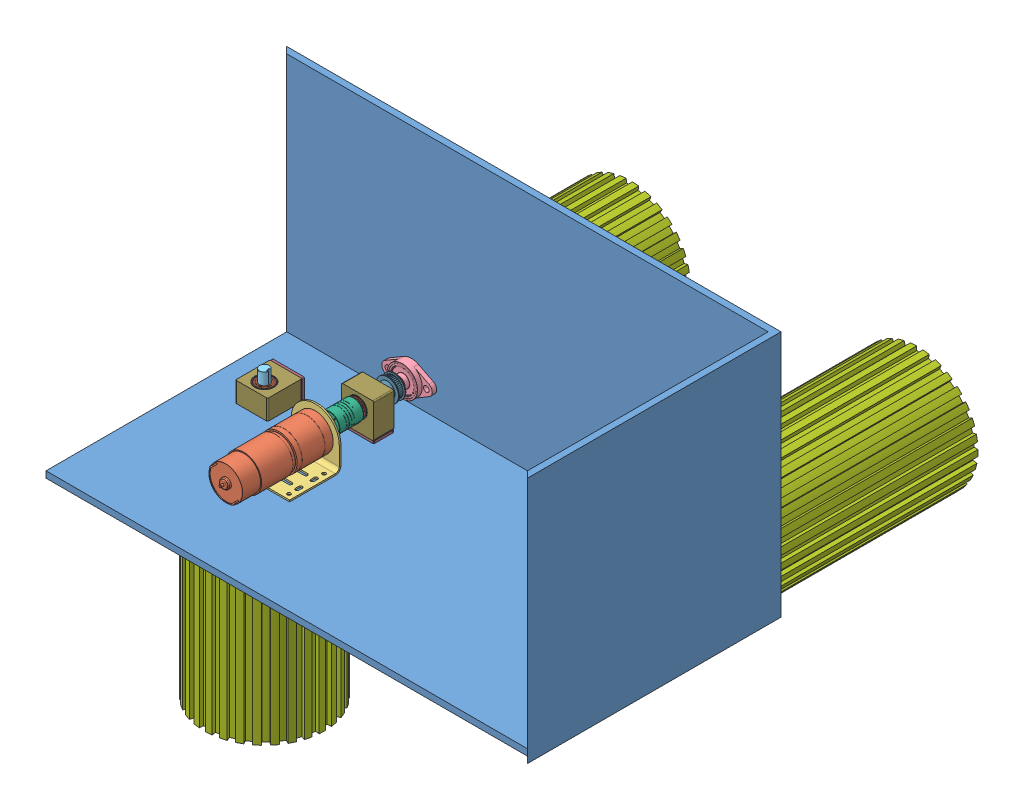
SolidWorks assembly moter in box assemly2, configuration Default. Lengths in mm.
Overall size (629.9 614.4 580.4).
108 component instances, 14 part files, 29 mates.
Components (placement in the parent):
- box-1: box [Default] at (214.7869 209.4239 556.9442) size (616 308 316)
- Motor DC PG45-1: Motor DC PG45 [Default] at (70.1664 247.4239 638.3442) x (0.707107 0.707107 0) z (-0.707107 0.707107 0) size (45 146.01 45)
- Mounting Bracket Motor DC PG45 Orange-1: Mounting Bracket Motor DC PG45 Orange [Default] at (91.7552 243.9192 526.8442) x (-1 0 0) z (0 0 -1) size (60 60 63.93)
- KFL001 block flange ball bearing 12 diameter shaft-1: KFL001 block flange ball bearing 12 diameter shaft [Default] at (70.1664 247.4239 406.9442) x (-0.034258 0.999413 0) z (0.999413 0.034258 0) size (38 16 63)
- wheel shaft-1: wheel shaft [Default] at (70.1664 247.4239 234.5442) x (0.995554 -0.094191 0) z (-0.094191 -0.995554 0) size (12 354 12)
- Shaft_Coupler_6.35x12mm-1: Shaft_Coupler_6.35x12mm [По умолчанию] at (70.1664 247.4239 508.9442) x (0.647293 0.762241 0) z (-0.762241 0.647293 0) size (25.41 30 25.41)
- wheel rubber-1: wheel rubber [Default] at (70.1664 247.4239 134.5442) x (-0.995554 0.094191 0) z (0.094191 0.995554 0) size (149.8 250 150)
- wheel rim-1: wheel rim [Default] at (70.1664 247.4239 134.5442) x (-0.995554 0.094191 0) z (0.094191 0.995554 0) size (130 250 130)
- Bearing House v1.step-1: Bearing House v1.step [Default] at (70.1664 227.9239 462.9398) x (-1 0 0) z (0 1 0) size (40 25 45.94)
  - SKF_61901-2Z.step-1: SKF_61901-2Z.step [Default] at (0 -8 19.5) x (0 -1 0) z (0 0 1) size (6 24 24)
    - SKF_61901-2Z_ball1.step-1: SKF_61901-2Z_ball1.step [Default] at (6 16.2812 -5.2901) x (-1 0 0) z (0 0 1) size (3.18 3.17 3.17)
    - SKF_61901-2Z_ball1.step-2: SKF_61901-2Z_ball1.step [Default] at (6 11.7812 -8.5595) x (-1 0 0) z (0 0 1) size (3.18 3.17 3.17)
    - SKF_61901-2Z_ball1.step-3: SKF_61901-2Z_ball1.step [Default] at (6 6.2188 -8.5595) x (-1 0 0) z (0 0 1) size (3.18 3.17 3.17)
    - SKF_61901-2Z_ball1.step-4: SKF_61901-2Z_ball1.step [Default] at (6 1.7188 -5.2901) x (-1 0 0) z (0 0 1) size (3.18 3.17 3.17)
    - SKF_61901-2Z_ball1.step-5: SKF_61901-2Z_ball1.step [Default] at (6 0 0) x (-1 0 0) z (0 0 1) size (3.18 3.17 3.17)
    - SKF_61901-2Z_ball1.step-6: SKF_61901-2Z_ball1.step [Default] at (6 1.7188 5.2901) x (-1 0 0) z (0 0 1) size (3.18 3.17 3.17)
    - SKF_61901-2Z_ball1.step-7: SKF_61901-2Z_ball1.step [Default] at (6 6.2188 8.5595) x (-1 0 0) z (0 0 1) size (3.18 3.17 3.17)
    - SKF_61901-2Z_ball1.step-8: SKF_61901-2Z_ball1.step [Default] at (6 11.7812 8.5595) x (-1 0 0) z (0 0 1) size (3.18 3.17 3.17)
    - SKF_61901-2Z_ball1.step-9: SKF_61901-2Z_ball1.step [Default] at (6 16.2812 5.2901) x (-1 0 0) z (0 0 1) size (3.18 3.17 3.17)
    - SKF_61901-2Z_ball1.step-10: SKF_61901-2Z_ball1.step [Default] at (6 18 0) x (-1 0 0) z (0 0 1) size (3.18 3.17 3.17)
    - SKF_61901-2Z_or.step-1: SKF_61901-2Z_or.step [Default] x (1 0 0) z (0 0 -1) size (6 24 24)
    - SKF_61901-2Z_ir.step-1: SKF_61901-2Z_ir.step [Default] x (1 0 0) z (0 0 -1) size (6 21.4 21.4)
  - SKF_61901-2Z.step-2: SKF_61901-2Z.step [Default] at (0 5 19.5) x (0 1 0) z (0 0 1) size (6 24 24)
    - SKF_61901-2Z_ball1.step-1: SKF_61901-2Z_ball1.step [Default] at (6 16.2812 -5.2901) x (-1 0 0) z (0 0 1) size (3.18 3.17 3.17)
    - SKF_61901-2Z_ball1.step-2: SKF_61901-2Z_ball1.step [Default] at (6 11.7812 -8.5595) x (-1 0 0) z (0 0 1) size (3.18 3.17 3.17)
    - SKF_61901-2Z_ball1.step-3: SKF_61901-2Z_ball1.step [Default] at (6 6.2188 -8.5595) x (-1 0 0) z (0 0 1) size (3.18 3.17 3.17)
    - SKF_61901-2Z_ball1.step-4: SKF_61901-2Z_ball1.step [Default] at (6 1.7188 -5.2901) x (-1 0 0) z (0 0 1) size (3.18 3.17 3.17)
    - SKF_61901-2Z_ball1.step-5: SKF_61901-2Z_ball1.step [Default] at (6 0 0) x (-1 0 0) z (0 0 1) size (3.18 3.17 3.17)
    - SKF_61901-2Z_ball1.step-6: SKF_61901-2Z_ball1.step [Default] at (6 1.7188 5.2901) x (-1 0 0) z (0 0 1) size (3.18 3.17 3.17)
    - SKF_61901-2Z_ball1.step-7: SKF_61901-2Z_ball1.step [Default] at (6 6.2188 8.5595) x (-1 0 0) z (0 0 1) size (3.18 3.17 3.17)
    - SKF_61901-2Z_ball1.step-8: SKF_61901-2Z_ball1.step [Default] at (6 11.7812 8.5595) x (-1 0 0) z (0 0 1) size (3.18 3.17 3.17)
    - SKF_61901-2Z_ball1.step-9: SKF_61901-2Z_ball1.step [Default] at (6 16.2812 5.2901) x (-1 0 0) z (0 0 1) size (3.18 3.17 3.17)
    - SKF_61901-2Z_ball1.step-10: SKF_61901-2Z_ball1.step [Default] at (6 18 0) x (-1 0 0) z (0 0 1) size (3.18 3.17 3.17)
    - SKF_61901-2Z_or.step-1: SKF_61901-2Z_or.step [Default] x (1 0 0) z (0 0 -1) size (6 24 24)
    - SKF_61901-2Z_ir.step-1: SKF_61901-2Z_ir.step [Default] x (1 0 0) z (0 0 -1) size (6 21.4 21.4)
  - Universal Bearing Housing.step-1: Universal Bearing Housing.step [Default] at (0 11.0044 14.0358) x (1 0 0) z (0 -1 0) size (40 43 25)
  - Universal Bearing Housing Spacer.step-1: Universal Bearing Housing Spacer.step [Default] at (0 -1.5 -7.4) x (1 0 0) z (0 1 0) size (40 3 25)
- GT2 40T id 12mm bw 7mm-1: GT2 40T id 12mm bw 7mm [Výchozí] at (70.1664 247.4239 435.4442) x (0.924379 0.381477 0) z (0.381477 -0.924379 0) size (28.2 17 28.2)
- moter in box assemly2 - Copy-1: moter in box assemly2 - Copy [Default] at (370.7934 -0.1 0) size (173.81 173.65 354)
  - KFL001 block flange ball bearing 12 diameter shaft-1: KFL001 block flange ball bearing 12 diameter shaft [Default] at (58.0648 247.4239 406.9442) x (-0.381567 0.924341 0) z (0.924341 0.381567 0) size (38 16 63)
  - wheel shaft-1: wheel shaft [Default] at (58.0648 247.4239 234.5442) x (0.174278 -0.984697 0) z (-0.984697 -0.174278 0) size (12 354 12)
  - wheel rubber-1: wheel rubber [Default] at (58.0648 247.4239 134.5442) x (-0.174278 0.984697 0) z (0.984697 0.174278 0) size (149.8 250 150)
  - wheel rim-1: wheel rim [Default] at (58.0648 247.4239 134.5442) x (-0.174278 0.984697 0) z (0.984697 0.174278 0) size (130 250 130)
  - Bearing House v1.step-1: Bearing House v1.step [Default] at (58.0648 227.9239 462.9398) x (-1 0 0) z (0 1 0) size (40 25 45.94)
    - SKF_61901-2Z.step-1: SKF_61901-2Z.step [Default] at (0 -8 19.5) x (0 -1 0) z (0 0 1) size (6 24 24)
      - SKF_61901-2Z_ball1.step-1: SKF_61901-2Z_ball1.step [Default] at (6 16.2812 -5.2901) x (-1 0 0) z (0 0 1) size (3.18 3.17 3.17)
      - SKF_61901-2Z_ball1.step-2: SKF_61901-2Z_ball1.step [Default] at (6 11.7812 -8.5595) x (-1 0 0) z (0 0 1) size (3.18 3.17 3.17)
      - SKF_61901-2Z_ball1.step-3: SKF_61901-2Z_ball1.step [Default] at (6 6.2188 -8.5595) x (-1 0 0) z (0 0 1) size (3.18 3.17 3.17)
      - SKF_61901-2Z_ball1.step-4: SKF_61901-2Z_ball1.step [Default] at (6 1.7188 -5.2901) x (-1 0 0) z (0 0 1) size (3.18 3.17 3.17)
      - SKF_61901-2Z_ball1.step-5: SKF_61901-2Z_ball1.step [Default] at (6 0 0) x (-1 0 0) z (0 0 1) size (3.18 3.17 3.17)
      - SKF_61901-2Z_ball1.step-6: SKF_61901-2Z_ball1.step [Default] at (6 1.7188 5.2901) x (-1 0 0) z (0 0 1) size (3.18 3.17 3.17)
      - SKF_61901-2Z_ball1.step-7: SKF_61901-2Z_ball1.step [Default] at (6 6.2188 8.5595) x (-1 0 0) z (0 0 1) size (3.18 3.17 3.17)
      - SKF_61901-2Z_ball1.step-8: SKF_61901-2Z_ball1.step [Default] at (6 11.7812 8.5595) x (-1 0 0) z (0 0 1) size (3.18 3.17 3.17)
      - SKF_61901-2Z_ball1.step-9: SKF_61901-2Z_ball1.step [Default] at (6 16.2812 5.2901) x (-1 0 0) z (0 0 1) size (3.18 3.17 3.17)
      - SKF_61901-2Z_ball1.step-10: SKF_61901-2Z_ball1.step [Default] at (6 18 0) x (-1 0 0) z (0 0 1) size (3.18 3.17 3.17)
      - SKF_61901-2Z_or.step-1: SKF_61901-2Z_or.step [Default] x (1 0 0) z (0 0 -1) size (6 24 24)
      - SKF_61901-2Z_ir.step-1: SKF_61901-2Z_ir.step [Default] x (1 0 0) z (0 0 -1) size (6 21.4 21.4)
    - SKF_61901-2Z.step-2: SKF_61901-2Z.step [Default] at (0 5 19.5) x (0 1 0) z (0 0 1) size (6 24 24)
      - SKF_61901-2Z_ball1.step-1: SKF_61901-2Z_ball1.step [Default] at (6 16.2812 -5.2901) x (-1 0 0) z (0 0 1) size (3.18 3.17 3.17)
      - SKF_61901-2Z_ball1.step-2: SKF_61901-2Z_ball1.step [Default] at (6 11.7812 -8.5595) x (-1 0 0) z (0 0 1) size (3.18 3.17 3.17)
      - SKF_61901-2Z_ball1.step-3: SKF_61901-2Z_ball1.step [Default] at (6 6.2188 -8.5595) x (-1 0 0) z (0 0 1) size (3.18 3.17 3.17)
      - SKF_61901-2Z_ball1.step-4: SKF_61901-2Z_ball1.step [Default] at (6 1.7188 -5.2901) x (-1 0 0) z (0 0 1) size (3.18 3.17 3.17)
      - SKF_61901-2Z_ball1.step-5: SKF_61901-2Z_ball1.step [Default] at (6 0 0) x (-1 0 0) z (0 0 1) size (3.18 3.17 3.17)
      - SKF_61901-2Z_ball1.step-6: SKF_61901-2Z_ball1.step [Default] at (6 1.7188 5.2901) x (-1 0 0) z (0 0 1) size (3.18 3.17 3.17)
      - SKF_61901-2Z_ball1.step-7: SKF_61901-2Z_ball1.step [Default] at (6 6.2188 8.5595) x (-1 0 0) z (0 0 1) size (3.18 3.17 3.17)
      - SKF_61901-2Z_ball1.step-8: SKF_61901-2Z_ball1.step [Default] at (6 11.7812 8.5595) x (-1 0 0) z (0 0 1) size (3.18 3.17 3.17)
      - SKF_61901-2Z_ball1.step-9: SKF_61901-2Z_ball1.step [Default] at (6 16.2812 5.2901) x (-1 0 0) z (0 0 1) size (3.18 3.17 3.17)
      - SKF_61901-2Z_ball1.step-10: SKF_61901-2Z_ball1.step [Default] at (6 18 0) x (-1 0 0) z (0 0 1) size (3.18 3.17 3.17)
      - SKF_61901-2Z_or.step-1: SKF_61901-2Z_or.step [Default] x (1 0 0) z (0 0 -1) size (6 24 24)
      - SKF_61901-2Z_ir.step-1: SKF_61901-2Z_ir.step [Default] x (1 0 0) z (0 0 -1) size (6 21.4 21.4)
    - Universal Bearing Housing.step-1: Universal Bearing Housing.step [Default] at (0 11.0044 14.0358) x (1 0 0) z (0 -1 0) size (40 43 25)
    - Universal Bearing Housing Spacer.step-1: Universal Bearing Housing Spacer.step [Default] at (0 -1.5 -7.4) x (1 0 0) z (0 1 0) size (40 3 25)
  - GT2 40T id 12mm bw 7mm-1: GT2 40T id 12mm bw 7mm [Výchozí] at (58.0648 247.4239 435.4442) x (0.924379 0.381477 0) z (0.381477 -0.924379 0) size (28.2 17 28.2)
- moter in box assemly2 - Copy-2: moter in box assemly2 - Copy [Default] at (37.8575 -231.5203 252.3424) x (-1 0 0) z (0 1 0) size (173.81 173.65 354)
  - KFL001 block flange ball bearing 12 diameter shaft-1: KFL001 block flange ball bearing 12 diameter shaft [Default] at (58.0648 247.4239 406.9442) x (-0.381567 0.924341 0) z (0.924341 0.381567 0) size (38 16 63)
  - wheel shaft-1: wheel shaft [Default] at (58.0648 247.4239 234.5442) x (0.174278 -0.984697 0) z (-0.984697 -0.174278 0) size (12 354 12)
  - wheel rubber-1: wheel rubber [Default] at (58.0648 247.4239 134.5442) x (-0.174278 0.984697 0) z (0.984697 0.174278 0) size (149.8 250 150)
  - wheel rim-1: wheel rim [Default] at (58.0648 247.4239 134.5442) x (-0.174278 0.984697 0) z (0.984697 0.174278 0) size (130 250 130)
  - Bearing House v1.step-1: Bearing House v1.step [Default] at (58.0648 227.9239 462.9398) x (-1 0 0) z (0 1 0) size (40 25 45.94)
    - SKF_61901-2Z.step-1: SKF_61901-2Z.step [Default] at (0 -8 19.5) x (0 -1 0) z (0 0 1) size (6 24 24)
      - SKF_61901-2Z_ball1.step-1: SKF_61901-2Z_ball1.step [Default] at (6 16.2812 -5.2901) x (-1 0 0) z (0 0 1) size (3.18 3.17 3.17)
      - SKF_61901-2Z_ball1.step-2: SKF_61901-2Z_ball1.step [Default] at (6 11.7812 -8.5595) x (-1 0 0) z (0 0 1) size (3.18 3.17 3.17)
      - SKF_61901-2Z_ball1.step-3: SKF_61901-2Z_ball1.step [Default] at (6 6.2188 -8.5595) x (-1 0 0) z (0 0 1) size (3.18 3.17 3.17)
      - SKF_61901-2Z_ball1.step-4: SKF_61901-2Z_ball1.step [Default] at (6 1.7188 -5.2901) x (-1 0 0) z (0 0 1) size (3.18 3.17 3.17)
      - SKF_61901-2Z_ball1.step-5: SKF_61901-2Z_ball1.step [Default] at (6 0 0) x (-1 0 0) z (0 0 1) size (3.18 3.17 3.17)
      - SKF_61901-2Z_ball1.step-6: SKF_61901-2Z_ball1.step [Default] at (6 1.7188 5.2901) x (-1 0 0) z (0 0 1) size (3.18 3.17 3.17)
      - SKF_61901-2Z_ball1.step-7: SKF_61901-2Z_ball1.step [Default] at (6 6.2188 8.5595) x (-1 0 0) z (0 0 1) size (3.18 3.17 3.17)
      - SKF_61901-2Z_ball1.step-8: SKF_61901-2Z_ball1.step [Default] at (6 11.7812 8.5595) x (-1 0 0) z (0 0 1) size (3.18 3.17 3.17)
      - SKF_61901-2Z_ball1.step-9: SKF_61901-2Z_ball1.step [Default] at (6 16.2812 5.2901) x (-1 0 0) z (0 0 1) size (3.18 3.17 3.17)
      - SKF_61901-2Z_ball1.step-10: SKF_61901-2Z_ball1.step [Default] at (6 18 0) x (-1 0 0) z (0 0 1) size (3.18 3.17 3.17)
      - SKF_61901-2Z_or.step-1: SKF_61901-2Z_or.step [Default] x (1 0 0) z (0 0 -1) size (6 24 24)
      - SKF_61901-2Z_ir.step-1: SKF_61901-2Z_ir.step [Default] x (1 0 0) z (0 0 -1) size (6 21.4 21.4)
    - SKF_61901-2Z.step-2: SKF_61901-2Z.step [Default] at (0 5 19.5) x (0 1 0) z (0 0 1) size (6 24 24)
      - SKF_61901-2Z_ball1.step-1: SKF_61901-2Z_ball1.step [Default] at (6 16.2812 -5.2901) x (-1 0 0) z (0 0 1) size (3.18 3.17 3.17)
      - SKF_61901-2Z_ball1.step-2: SKF_61901-2Z_ball1.step [Default] at (6 11.7812 -8.5595) x (-1 0 0) z (0 0 1) size (3.18 3.17 3.17)
      - SKF_61901-2Z_ball1.step-3: SKF_61901-2Z_ball1.step [Default] at (6 6.2188 -8.5595) x (-1 0 0) z (0 0 1) size (3.18 3.17 3.17)
      - SKF_61901-2Z_ball1.step-4: SKF_61901-2Z_ball1.step [Default] at (6 1.7188 -5.2901) x (-1 0 0) z (0 0 1) size (3.18 3.17 3.17)
      - SKF_61901-2Z_ball1.step-5: SKF_61901-2Z_ball1.step [Default] at (6 0 0) x (-1 0 0) z (0 0 1) size (3.18 3.17 3.17)
      - SKF_61901-2Z_ball1.step-6: SKF_61901-2Z_ball1.step [Default] at (6 1.7188 5.2901) x (-1 0 0) z (0 0 1) size (3.18 3.17 3.17)
      - SKF_61901-2Z_ball1.step-7: SKF_61901-2Z_ball1.step [Default] at (6 6.2188 8.5595) x (-1 0 0) z (0 0 1) size (3.18 3.17 3.17)
      - SKF_61901-2Z_ball1.step-8: SKF_61901-2Z_ball1.step [Default] at (6 11.7812 8.5595) x (-1 0 0) z (0 0 1) size (3.18 3.17 3.17)
      - SKF_61901-2Z_ball1.step-9: SKF_61901-2Z_ball1.step [Default] at (6 16.2812 5.2901) x (-1 0 0) z (0 0 1) size (3.18 3.17 3.17)
      - SKF_61901-2Z_ball1.step-10: SKF_61901-2Z_ball1.step [Default] at (6 18 0) x (-1 0 0) z (0 0 1) size (3.18 3.17 3.17)
      - SKF_61901-2Z_or.step-1: SKF_61901-2Z_or.step [Default] x (1 0 0) z (0 0 -1) size (6 24 24)
      - SKF_61901-2Z_ir.step-1: SKF_61901-2Z_ir.step [Default] x (1 0 0) z (0 0 -1) size (6 21.4 21.4)
    - Universal Bearing Housing.step-1: Universal Bearing Housing.step [Default] at (0 11.0044 14.0358) x (1 0 0) z (0 -1 0) size (40 43 25)
    - Universal Bearing Housing Spacer.step-1: Universal Bearing Housing Spacer.step [Default] at (0 -1.5 -7.4) x (1 0 0) z (0 1 0) size (40 3 25)
  - GT2 40T id 12mm bw 7mm-1: GT2 40T id 12mm bw 7mm [Výchozí] at (58.0648 247.4239 435.4442) x (0.924379 0.381477 0) z (0.381477 -0.924379 0) size (28.2 17 28.2)
Mates (geometry in assembly coordinates):
- Concentric1: concentric aligned: circle of Motor DC PG45-1; circle of Mounting Bracket Motor DC PG45 Orange-1
- Coincident1: coincident aligned: plane of Motor DC PG45-1 through (70.1664 247.4239 526.8442) normal (0 0 -1); circle of Mounting Bracket Motor DC PG45 Orange-1
- Parallel1: parallel anti-aligned: line of box-1 through (-85.2131 217.4239 406.9442) axis (0 0 1); line of Mounting Bracket Motor DC PG45 Orange-1 through (40.1664 217.4239 588.7742) axis (0 0 -1)
- Coincident2: coincident anti-aligned: plane of box-1 through (214.7869 217.4239 556.9442) normal (0 1 0); plane of Mounting Bracket Motor DC PG45 Orange-1 through (91.7552 217.4239 526.8442) normal (0 -1 0)
- Coincident3: coincident anti-aligned: plane of box-1 through (214.7869 217.4239 556.9442) normal (0 1 0); plane of Mounting Bracket Motor DC PG45 Orange-1 through (91.7552 217.4239 526.8442) normal (0 -1 0)
- Concentric2: concentric aligned: circle of Motor DC PG45-1; circle of Mounting Bracket Motor DC PG45 Orange-1
- Concentric3: concentric anti-aligned: circle of Motor DC PG45-1; circle of KFL001 block flange ball bearing 12 diameter shaft-1
- Concentric6: concentric anti-aligned: circle of Motor DC PG45-1; circle of Shaft_Coupler_6.35x12mm-1
- Concentric8: concentric aligned: circle of KFL001 block flange ball bearing 12 diameter shaft-1; circle of wheel shaft-1
- Distance2: distance = 9.6 mm anti-aligned: plane of Shaft_Coupler_6.35x12mm-1 through (70.1664 247.4239 508.9442) normal (0 0 1); plane of Motor DC PG45-1 through (70.1664 247.4239 499.3442) normal (0 0 -1)
- Coincident10: coincident anti-aligned: plane of box-1 through (214.7869 517.4239 406.9442) normal (0 0 1); plane of KFL001 block flange ball bearing 12 diameter shaft-1 through (70.1664 247.4239 406.9442) normal (0 0 -1)
- Lock3: lock: unknown of wheel rubber-1; unknown of wheel rim-1
- Concentric10: concentric anti-aligned: cylinder of wheel shaft-1 through (70.1664 247.4239 134.5442) axis (0 0 -1) radius 6; circle of wheel rim-1
- Concentric13: concentric anti-aligned: circle of wheel shaft-1; circle of Bearing House v1.step-1/SKF_61901-2Z.step-1/SKF_61901-2Z_ir.step-1
- Parallel5: parallel aligned: line of box-1 through (-93.2131 209.4239 398.9442) axis (1 0 0); line of Bearing House v1.step-1/Universal Bearing Housing Spacer.step-1 through (51.1664 217.5239 448.9398) axis (1 0 0)
- Concentric14: concentric aligned: circle of wheel shaft-1; circle of GT2 40T id 12mm bw 7mm-1
- Lock7: lock: unknown of wheel shaft-1; unknown of Shaft_Coupler_6.35x12mm-1
- Distance5: distance = 5 mm anti-aligned: plane of Bearing House v1.step-1/Universal Bearing Housing.step-1 through (70.1664 241.9597 473.9442) normal (0 0 1); plane of Shaft_Coupler_6.35x12mm-1 through (70.1664 247.4239 478.9442) normal (0 0 -1)
- Distance6: distance = 5 mm anti-aligned: plane of GT2 40T id 12mm bw 7mm-1 through (70.1664 247.4239 443.9442) normal (0 0 1); plane of Bearing House v1.step-1/Universal Bearing Housing.step-1 through (70.1664 241.9597 448.9442) normal (0 0 -1)
- Distance7: distance = 5 mm anti-aligned: plane of KFL001 block flange ball bearing 12 diameter shaft-1 through (70.1664 247.4239 422.9442) normal (0 0 1); plane of GT2 40T id 12mm bw 7mm-1 through (70.1664 247.4239 427.9442) normal (0 0 -1)
- Coincident13: coincident anti-aligned: plane of wheel shaft-1 through (70.1664 247.4239 134.5442) normal (0 0 -1); circle of wheel rim-1
- Coincident14: coincident anti-aligned: line of wheel shaft-1 through (67.6425 241.9806 134.5442) axis (0 0 1); line of wheel rim-1 through (67.6425 241.9806 154.5442) axis (0 0 -1)
- Coincident15: coincident anti-aligned: plane of box-1 through (214.7869 217.4239 556.9442) normal (0 1 0); plane of moter in box assemly2 - Copy-1/Bearing House v1.step-1/Universal Bearing Housing Spacer.step-1 through (428.8582 217.4239 461.4398) normal (0 -1 0)
- Parallel6: parallel anti-aligned: line of box-1 through (-85.2131 217.4239 406.9442) axis (0 0 1); line of moter in box assemly2 - Copy-1/Bearing House v1.step-1/Universal Bearing Housing Spacer.step-1 through (408.8582 217.4239 472.9398) axis (0 0 -1)
- Parallel7: parallel anti-aligned: line of box-1 through (-85.2131 217.4239 706.9442) axis (1 0 0); line of moter in box assemly2 - Copy-1/Bearing House v1.step-1/Universal Bearing Housing Spacer.step-1 through (447.8582 217.4239 473.9398) axis (-1 0 0)
- Coincident18: coincident anti-aligned: plane of box-1 through (214.7869 517.4239 406.9442) normal (0 0 1); plane of moter in box assemly2 - Copy-1/KFL001 block flange ball bearing 12 diameter shaft-1 through (428.8582 247.3239 406.9442) normal (0 0 -1)
- Coincident19: coincident anti-aligned: plane of box-1 through (214.7869 217.4239 556.9442) normal (0 1 0); plane of moter in box assemly2 - Copy-2/Bearing House v1.step-1/Universal Bearing Housing.step-1 through (-20.2072 217.4239 494.302) normal (0 -1 0)
- Parallel8: parallel anti-aligned: line of box-1 through (-85.2131 217.4239 406.9442) axis (0 0 1); line of moter in box assemly2 - Copy-2/Bearing House v1.step-1/Universal Bearing Housing.step-1 through (-40.2072 217.4239 514.302) axis (0 0 -1)
- Coincident21: coincident anti-aligned: plane of box-1 through (214.7869 217.4239 556.9442) normal (0 1 0); plane of moter in box assemly2 - Copy-2/Bearing House v1.step-1/Universal Bearing Housing.step-1 through (-20.2072 217.4239 494.302) normal (0 -1 0)
